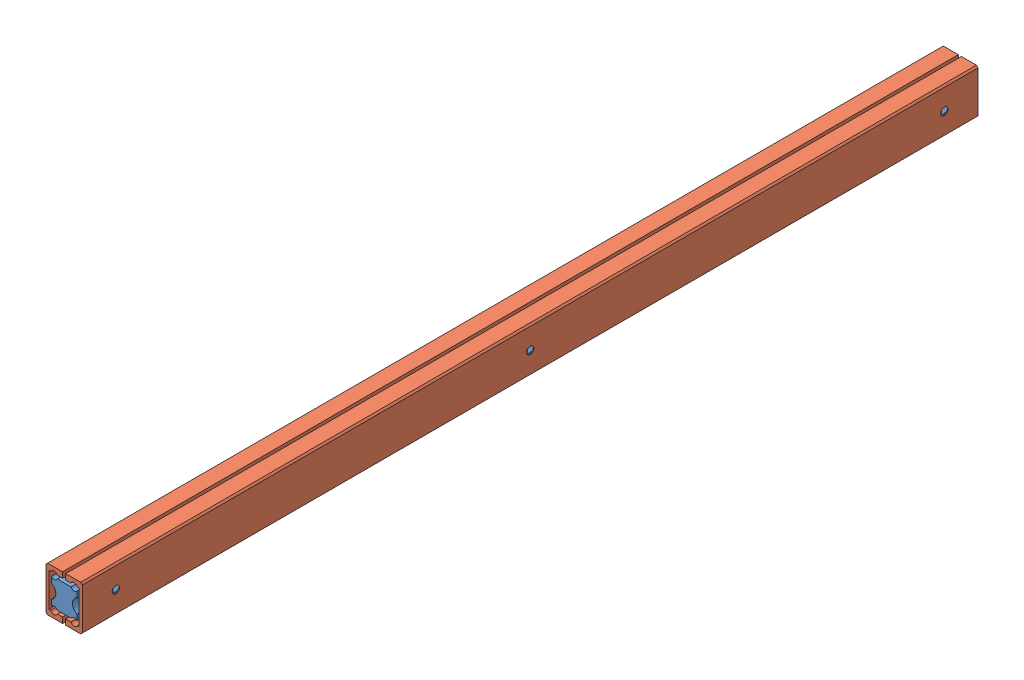
SolidWorks assembly SAR340, configuration Default. Lengths in mm.
Overall size (16.2 20 400).
7 component instances, 3 part files, 0 mates.
Components (placement in the parent):
- _SAR340_40_r_2-1: _SAR340_40_r_2 [Default] at origin size (11.4 12.1 400)
- _SAR340_40_b_4-1: _SAR340_40_b_4 [Default] at (5 -3.95 0) size (7.4 20 400)
- _SAR340_40_b_4-2: _SAR340_40_b_4 [Default] at (6.4 16.05 0) x (-1 0 0) z (0 0 1) size (7.4 20 400)
- _SAR340_ba_7-1: _SAR340_ba_7 [Default] at (1.2 -0.75 141.5) size (3.25 3.25 120.25)
- _SAR340_ba_7-2: _SAR340_ba_7 [Default] at (10.2 -0.75 141.5) size (3.25 3.25 120.25)
- _SAR340_ba_7-3: _SAR340_ba_7 [Default] at (1.2 12.85 141.5) size (3.25 3.25 120.25)
- _SAR340_ba_7-4: _SAR340_ba_7 [Default] at (10.2 12.85 141.5) size (3.25 3.25 120.25)
